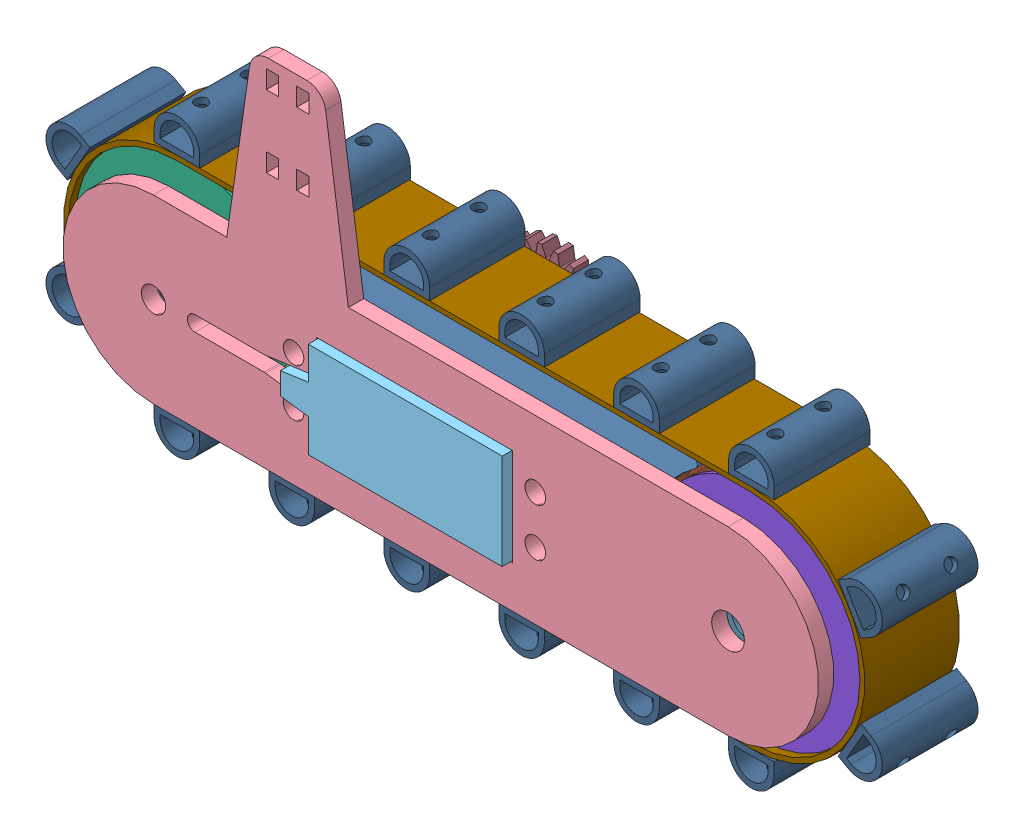
SolidWorks assembly DriveTread Assembly_L, configuration Default. Lengths in mm.
Overall size (178.72 86.48 42.8).
82 component instances, 14 part files, 28 mates.
Components (placement in the parent):
- tread runner-3: tread runner [Default] at (113.4402 41.5963 5.7004) x (-1 0 0) z (0 0 1) size (94.4 45.38 1.65)
- drive spacer_mid-1: drive spacer_mid [Default] at (14.0238 -0.101 14.8444) size (83.18 38.02 14.99)
- tread runner-4: tread runner [Default] at (113.4402 41.5963 22.3374) x (-1 0 0) z (0 0 1) size (94.4 45.38 1.65)
- drive spacer_out-1: drive spacer_out [Default] at (19.9176 6.2078 23.9884) size (78.33 25.4 3.2)
- drive plate_out-1: drive plate_out [Default] at (0 0 27.1888) size (157.83 74.55 3.2)
- Servo_ContRotation-3: Servo_ContRotation [Default] at (74.747 28.9078 5.7004) x (0 -1 0) z (0 0 -1) size (20 55.5 42.8)
- DriveWheel-4: DriveWheel [Default] at (5.674 -10.8624 -21.7598) x (0.924613 0.380909 0) z (0 0 1) size (45.38 45.43 18.29)
  - Custom Axle Drive_LEGO UWheel_6x3-1: Custom Axle Drive_LEGO UWheel_6x3 [Default] at (6.0935 29.6872 36.6042) size (45.38 45.43 18.29)
  - WheelPlates w-Custom Axle-1: WheelPlates w-Custom Axle [Default] at (6.0935 29.6872 42.497) x (-1 0 0) z (0 0 1) size (28.95 30.08 3.2)
  - WheelPlates w-Custom Axle-2: WheelPlates w-Custom Axle [Default] at (6.0935 29.6872 27.511) x (-1 0 0) z (0 0 1) size (28.95 30.08 3.2)
- Custom Axle Float_LEGO UWheel_6x-5: Custom Axle Float_LEGO UWheel_6x [Default] at (120.015 18.9078 14.8444) x (0.969727 -0.244192 0) z (0 0 1) size (45.38 45.38 18.29)
- tread-2: tread [Default] at (0 -3.7808 15.6064) size (178.18 61.66 20)
  - tread_base-1: tread_base [Default] at origin size (167.39 47.38 19.81)
  - D-Lug_Terrain-1: D-Lug_Terrain [Default] at (0 48.7584 -10.094) size (9.53 7.14 20)
  - D-Lug_Terrain-2: D-Lug_Terrain [Default] at (-22.5771 35.7234 -10.094) x (0.5 0.866025 0) z (0 0 1) size (9.53 7.14 20)
  - D-Lug_Terrain-3: D-Lug_Terrain [Default] at (-22.5771 9.6536 -10.094) x (-0.5 0.866025 0) z (0 0 1) size (9.53 7.14 20)
  - D-Lug_Terrain-4: D-Lug_Terrain [Default] at (0 -3.3813 -10.094) x (-1 0 0) z (0 0 1) size (9.53 7.14 20)
  - D-Lug_Terrain-6: D-Lug_Terrain [Default] at (24.003 48.7584 -10.094) size (9.53 7.14 20)
  - D-Lug_Terrain-7: D-Lug_Terrain [Default] at (48.006 48.7584 -10.094) size (9.53 7.14 20)
  - D-Lug_Terrain-8: D-Lug_Terrain [Default] at (72.009 48.7584 -10.094) size (9.53 7.14 20)
  - D-Lug_Terrain-9: D-Lug_Terrain [Default] at (96.012 48.7584 -10.094) size (9.53 7.14 20)
  - D-Lug_Terrain-10: D-Lug_Terrain [Default] at (120.015 48.7584 -10.094) size (9.53 7.14 20)
  - D-Lug_Terrain-11: D-Lug_Terrain [Default] at (24.003 -3.3813 -10.094) x (-1 0 0) z (0 0 1) size (9.53 7.14 20)
  - D-Lug_Terrain-12: D-Lug_Terrain [Default] at (48.006 -3.3813 -10.094) x (-1 0 0) z (0 0 1) size (9.53 7.14 20)
  - D-Lug_Terrain-13: D-Lug_Terrain [Default] at (72.009 -3.3813 -10.094) x (-1 0 0) z (0 0 1) size (9.53 7.14 20)
  - D-Lug_Terrain-14: D-Lug_Terrain [Default] at (96.012 -3.3813 -10.094) x (-1 0 0) z (0 0 1) size (9.53 7.14 20)
  - D-Lug_Terrain-15: D-Lug_Terrain [Default] at (142.5921 35.7234 -10.094) x (0.5 -0.866025 0) z (0 0 1) size (9.53 7.14 20)
  - D-Lug_Terrain-16: D-Lug_Terrain [Default] at (142.5921 9.6536 -10.094) x (-0.5 -0.866025 0) z (0 0 1) size (9.53 7.14 20)
  - D-Lug_Terrain-17: D-Lug_Terrain [Default] at (120.015 -3.3813 -10.094) x (-1 0 0) z (0 0 1) size (9.53 7.14 20)
  - Drive Lug_x-1: Drive Lug_x [Default] at (-2.7045 0 0) size (5.84 6.24 14.92)
    - Drive Lug_x-1: Drive Lug_x [Default] at origin size (5.41 3.2 14.92)
    - 97334A104_NYLON SOCKET HEAD CAP SCREW-1: 97334A104_NYLON SOCKET HEAD CAP SCREW [97334A104] at (2.7045 0.0254 0) x (0.302379 0 0.953188) z (0 -1 0) size (4.65 4.65 6.24)
  - Drive Lug_x-2: Drive Lug_x [Default] at (-21.0011 13.6864 0) x (0.5 -0.866025 0) z (0 0 1) size (5.84 6.24 14.92)
    - Drive Lug_x-1: Drive Lug_x [Default] at origin size (5.41 3.2 14.92)
    - 97334A104_NYLON SOCKET HEAD CAP SCREW-1: 97334A104_NYLON SOCKET HEAD CAP SCREW [97334A104] at (2.7045 0.0254 0) x (0.302379 0 0.953188) z (0 -1 0) size (4.65 4.65 6.24)
  - Drive Lug_x-3: Drive Lug_x [Default] at (-18.2966 36.375 0) x (-0.5 -0.866025 0) z (0 0 1) size (5.84 6.24 14.92)
    - Drive Lug_x-1: Drive Lug_x [Default] at origin size (5.41 3.2 14.92)
    - 97334A104_NYLON SOCKET HEAD CAP SCREW-1: 97334A104_NYLON SOCKET HEAD CAP SCREW [97334A104] at (2.7045 0.0254 0) x (0.302379 0 0.953188) z (0 -1 0) size (4.65 4.65 6.24)
  - Drive Lug_x-4: Drive Lug_x [Default] at (2.7045 45.3771 0) x (-1 0 0) z (0 0 1) size (5.84 6.24 14.92)
    - Drive Lug_x-1: Drive Lug_x [Default] at origin size (5.41 3.2 14.92)
    - 97334A104_NYLON SOCKET HEAD CAP SCREW-1: 97334A104_NYLON SOCKET HEAD CAP SCREW [97334A104] at (2.7045 0.0254 0) x (0.302379 0 0.953188) z (0 -1 0) size (4.65 4.65 6.24)
  - Drive Lug_x-17: Drive Lug_x [Default] at (21.2985 0 0) size (5.84 6.24 14.92)
    - Drive Lug_x-1: Drive Lug_x [Default] at origin size (5.41 3.2 14.92)
    - 97334A104_NYLON SOCKET HEAD CAP SCREW-1: 97334A104_NYLON SOCKET HEAD CAP SCREW [97334A104] at (2.7045 0.0254 0) x (0.302379 0 0.953188) z (0 -1 0) size (4.65 4.65 6.24)
  - Drive Lug_x-18: Drive Lug_x [Default] at (45.3015 0 0) size (5.84 6.24 14.92)
    - Drive Lug_x-1: Drive Lug_x [Default] at origin size (5.41 3.2 14.92)
    - 97334A104_NYLON SOCKET HEAD CAP SCREW-1: 97334A104_NYLON SOCKET HEAD CAP SCREW [97334A104] at (2.7045 0.0254 0) x (0.302379 0 0.953188) z (0 -1 0) size (4.65 4.65 6.24)
  - Drive Lug_x-19: Drive Lug_x [Default] at (69.3045 0 0) size (5.84 6.24 14.92)
    - Drive Lug_x-1: Drive Lug_x [Default] at origin size (5.41 3.2 14.92)
    - 97334A104_NYLON SOCKET HEAD CAP SCREW-1: 97334A104_NYLON SOCKET HEAD CAP SCREW [97334A104] at (2.7045 0.0254 0) x (0.302379 0 0.953188) z (0 -1 0) size (4.65 4.65 6.24)
  - Drive Lug_x-20: Drive Lug_x [Default] at (93.3075 0 0) size (5.84 6.24 14.92)
    - Drive Lug_x-1: Drive Lug_x [Default] at origin size (5.41 3.2 14.92)
    - 97334A104_NYLON SOCKET HEAD CAP SCREW-1: 97334A104_NYLON SOCKET HEAD CAP SCREW [97334A104] at (2.7045 0.0254 0) x (0.302379 0 0.953188) z (0 -1 0) size (4.65 4.65 6.24)
  - Drive Lug_x-21: Drive Lug_x [Default] at (117.3105 0 0) size (5.84 6.24 14.92)
    - Drive Lug_x-1: Drive Lug_x [Default] at origin size (5.41 3.2 14.92)
    - 97334A104_NYLON SOCKET HEAD CAP SCREW-1: 97334A104_NYLON SOCKET HEAD CAP SCREW [97334A104] at (2.7045 0.0254 0) x (0.302379 0 0.953188) z (0 -1 0) size (4.65 4.65 6.24)
  - Drive Lug_x-22: Drive Lug_x [Default] at (138.3116 9.0021 0) x (0.5 0.866025 0) z (0 0 1) size (5.84 6.24 14.92)
    - Drive Lug_x-1: Drive Lug_x [Default] at origin size (5.41 3.2 14.92)
    - 97334A104_NYLON SOCKET HEAD CAP SCREW-1: 97334A104_NYLON SOCKET HEAD CAP SCREW [97334A104] at (2.7045 0.0254 0) x (0.302379 0 0.953188) z (0 -1 0) size (4.65 4.65 6.24)
  - Drive Lug_x-23: Drive Lug_x [Default] at (141.0161 31.6907 0) x (-0.5 0.866025 0) z (0 0 1) size (5.84 6.24 14.92)
    - Drive Lug_x-1: Drive Lug_x [Default] at origin size (5.41 3.2 14.92)
    - 97334A104_NYLON SOCKET HEAD CAP SCREW-1: 97334A104_NYLON SOCKET HEAD CAP SCREW [97334A104] at (2.7045 0.0254 0) x (0.302379 0 0.953188) z (0 -1 0) size (4.65 4.65 6.24)
  - Drive Lug_x-24: Drive Lug_x [Default] at (122.7195 45.3771 0) x (-1 0 0) z (0 0 1) size (5.84 6.24 14.92)
    - Drive Lug_x-1: Drive Lug_x [Default] at origin size (5.41 3.2 14.92)
    - 97334A104_NYLON SOCKET HEAD CAP SCREW-1: 97334A104_NYLON SOCKET HEAD CAP SCREW [97334A104] at (2.7045 0.0254 0) x (0.302379 0 0.953188) z (0 -1 0) size (4.65 4.65 6.24)
  - Drive Lug_x-13: Drive Lug_x [Default] at (26.7075 45.3771 0) x (-1 0 0) z (0 0 1) size (5.84 6.24 14.92)
    - Drive Lug_x-1: Drive Lug_x [Default] at origin size (5.41 3.2 14.92)
    - 97334A104_NYLON SOCKET HEAD CAP SCREW-1: 97334A104_NYLON SOCKET HEAD CAP SCREW [97334A104] at (2.7045 0.0254 0) x (0.302379 0 0.953188) z (0 -1 0) size (4.65 4.65 6.24)
  - Drive Lug_x-14: Drive Lug_x [Default] at (50.7105 45.3771 0) x (-1 0 0) z (0 0 1) size (5.84 6.24 14.92)
    - Drive Lug_x-1: Drive Lug_x [Default] at origin size (5.41 3.2 14.92)
    - 97334A104_NYLON SOCKET HEAD CAP SCREW-1: 97334A104_NYLON SOCKET HEAD CAP SCREW [97334A104] at (2.7045 0.0254 0) x (0.302379 0 0.953188) z (0 -1 0) size (4.65 4.65 6.24)
  - Drive Lug_x-15: Drive Lug_x [Default] at (74.7135 45.3771 0) x (-1 0 0) z (0 0 1) size (5.84 6.24 14.92)
    - Drive Lug_x-1: Drive Lug_x [Default] at origin size (5.41 3.2 14.92)
    - 97334A104_NYLON SOCKET HEAD CAP SCREW-1: 97334A104_NYLON SOCKET HEAD CAP SCREW [97334A104] at (2.7045 0.0254 0) x (0.302379 0 0.953188) z (0 -1 0) size (4.65 4.65 6.24)
  - Drive Lug_x-16: Drive Lug_x [Default] at (98.7165 45.3771 0) x (-1 0 0) z (0 0 1) size (5.84 6.24 14.92)
    - Drive Lug_x-1: Drive Lug_x [Default] at origin size (5.41 3.2 14.92)
    - 97334A104_NYLON SOCKET HEAD CAP SCREW-1: 97334A104_NYLON SOCKET HEAD CAP SCREW [97334A104] at (2.7045 0.0254 0) x (0.302379 0 0.953188) z (0 -1 0) size (4.65 4.65 6.24)
- 24T Gear _Futaba Spline-2: 24T Gear _Futaba Spline [Default] at (44.647 18.9078 -10.5017) size (25.67 25.67 3.2)
- wheelspacer-1: wheelspacer [Default] at (120.015 18.9078 23.9884) size (19.05 19.05 2.31)
- wheelspacer-2: wheelspacer [Default] at (0 18.9078 23.9884) size (19.05 19.05 2.31)
- wheelspacer-3: wheelspacer [Default] at (120.015 18.9078 3.389) size (19.05 19.05 2.31)
- wheelspacer-4: wheelspacer [Default] at (0 18.9078 3.389) size (19.05 19.05 2.31)
Mates (geometry in assembly coordinates):
- Coincident6: coincident: plane of tread runner-3 through (120.015 18.9078 7.3514) normal (0 0 1); plane of drive spacer_mid-1 through (0 18.9078 7.3514) normal (0 0 -1)
- Coincident8: coincident: plane of drive spacer_mid-1 through (0 18.9078 22.3374) normal (0 0 1); plane of tread runner-4 through (120.015 18.9078 22.3374) normal (0 0 -1)
- Concentric15: concentric: cylinder of drive spacer_mid-1 through (29.247 13.9078 1.2448) axis (0 0 1) radius 2.159; cylinder of tread runner-4 through (29.247 13.9078 16.2308) axis (0 0 1) radius 2.159
- Coincident9: coincident: plane of tread runner-4 through (120.015 18.9078 23.9884) normal (0 0 1); plane of drive spacer_out-1 through (0 18.9078 23.9884) normal (0 0 -1)
- Concentric17: concentric: cylinder of tread runner-4 through (29.247 13.9078 16.2308) axis (0 0 1) radius 2.159; cylinder of drive spacer_out-1 through (29.247 13.9078 17.8818) axis (0 0 1) radius 2.159
- Concentric18: concentric: cylinder of tread runner-4 through (79.747 23.9078 16.2308) axis (0 0 1) radius 2.159; cylinder of drive spacer_out-1 through (79.747 23.9078 17.8818) axis (0 0 1) radius 2.159
- Coincident11: coincident: plane of drive spacer_out-1 through (0 18.9078 27.1888) normal (0 0 1); plane of drive plate_out-1 through (0 18.9078 27.1888) normal (0 0 -1)
- Concentric21: concentric: cylinder of drive spacer_out-1 through (29.247 23.9078 17.8818) axis (0 0 1) radius 2.159; cylinder of drive plate_out-1 through (29.247 23.9078 30.3892) axis (0 0 -1) radius 2.159
- Concentric39: concentric: cylinder of tread runner-3 through (79.747 13.9078 -0.4062) axis (0 0 1) radius 2.159; cylinder of drive spacer_mid-1 through (79.747 13.9078 1.2448) axis (0 0 1) radius 2.159
- Concentric40: concentric: cylinder of tread runner-3 through (29.247 23.9078 -0.4062) axis (0 0 1) radius 2.159; cylinder of drive spacer_mid-1 through (29.247 23.9078 1.2448) axis (0 0 1) radius 2.159
- Coincident22: coincident: plane of tread runner-3 through (120.015 18.9078 5.7004) normal (0 0 -1); plane of Servo_ContRotation-3 through (74.747 28.9078 5.7004) normal (0 0 1)
- Concentric45: concentric: cylinder of drive spacer_mid-1 through (29.247 23.9078 1.2448) axis (0 0 1) radius 2.159; cylinder of Servo_ContRotation-3 through (29.247 23.9078 3.2004) axis (0 0 1) radius 2.25
- Coincident25: coincident: plane of tread runner-4 through (120.015 18.9078 23.9884) normal (0 0 1); plane of DriveWheel-4/Custom Axle Drive_LEGO UWheel_6x3-1 through (0 18.9078 23.9884) normal (0 0 1)
- Coincident26: coincident: plane of tread runner-4 through (120.015 18.9078 23.9884) normal (0 0 1); plane of Custom Axle Float_LEGO UWheel_6x-5 through (120.015 18.9078 23.9884) normal (0 0 1)
- Concentric62: concentric: cylinder of drive spacer_mid-1 through (92.3222 23.9078 1.2448) axis (0 0 1) radius 2.159; cylinder of tread runner-4 through (92.3222 23.9078 16.2308) axis (0 0 1) radius 2.159
- Concentric64: concentric: cylinder of drive plate_out-1 through (120.015 18.9078 30.3892) axis (0 0 -1) radius 3.429; cylinder of tread-2/tread_base-1 through (120.015 18.9078 25.5124) axis (0 0 -1) radius 22.6885
- Coincident34: coincident: plane of Custom Axle Float_LEGO UWheel_6x-5 through (120.015 18.9078 5.7004) normal (0 0 -1); plane of tread-2/tread_base-1 through (120.015 18.9078 5.7004) normal (0 0 -1)
- Coincident36: coincident: plane of Servo_ContRotation-3 through (44.647 18.9078 -10.5017) normal (0 0 -1); plane of 24T Gear _Futaba Spline-2 through (44.647 18.9078 -10.5017) normal (0 0 -1)
- Concentric68: concentric: cylinder of Servo_ContRotation-3 through (44.647 18.9078 -10.5017) axis (0 0 1) radius 2.794; circle of 24T Gear _Futaba Spline-2
- Concentric76: concentric: cylinder of DriveWheel-4/Custom Axle Drive_LEGO UWheel_6x3-1 through (0 18.9078 23.9884) axis (0 0 -1) radius 22.6885; cylinder of tread-2/tread_base-1 through (0 18.9078 25.5124) axis (0 0 -1) radius 22.6885
- Coincident37: coincident: plane of Custom Axle Float_LEGO UWheel_6x-5 through (120.015 18.9078 23.9884) normal (0 0 1); plane of wheelspacer-1 through (120.015 18.9078 23.9884) normal (0 0 -1)
- Concentric77: concentric: cylinder of Custom Axle Float_LEGO UWheel_6x-5 through (120.015 18.9078 23.9884) axis (0 0 -1) radius 3.429; cylinder of wheelspacer-1 through (120.015 18.9078 26.2998) axis (0 0 -1) radius 3.429
- Coincident38: coincident: plane of DriveWheel-4/Custom Axle Drive_LEGO UWheel_6x3-1 through (0 18.9078 23.9884) normal (0 0 1); plane of wheelspacer-2 through (0 18.9078 23.9884) normal (0 0 -1)
- Concentric78: concentric: cylinder of drive plate_out-1 through (0 18.9078 30.3892) axis (0 0 -1) radius 2.54; cylinder of wheelspacer-2 through (0 18.9078 26.2998) axis (0 0 -1) radius 9.525
- Coincident39: coincident: plane of Custom Axle Float_LEGO UWheel_6x-5 through (120.015 18.9078 5.7004) normal (0 0 -1); plane of wheelspacer-3 through (120.015 18.9078 5.7004) normal (0 0 1)
- Concentric79: concentric: cylinder of Custom Axle Float_LEGO UWheel_6x-5 through (120.015 18.9078 23.9884) axis (0 0 -1) radius 3.429; cylinder of wheelspacer-3 through (120.015 18.9078 5.7004) axis (0 0 -1) radius 3.429
- Coincident40: coincident: plane of DriveWheel-4/Custom Axle Drive_LEGO UWheel_6x3-1 through (0 18.9078 5.7004) normal (0 0 -1); plane of wheelspacer-4 through (0 18.9078 5.7004) normal (0 0 1)
- Concentric80: concentric: cylinder of drive plate_out-1 through (0 18.9078 30.3892) axis (0 0 -1) radius 2.54; circle of wheelspacer-4
